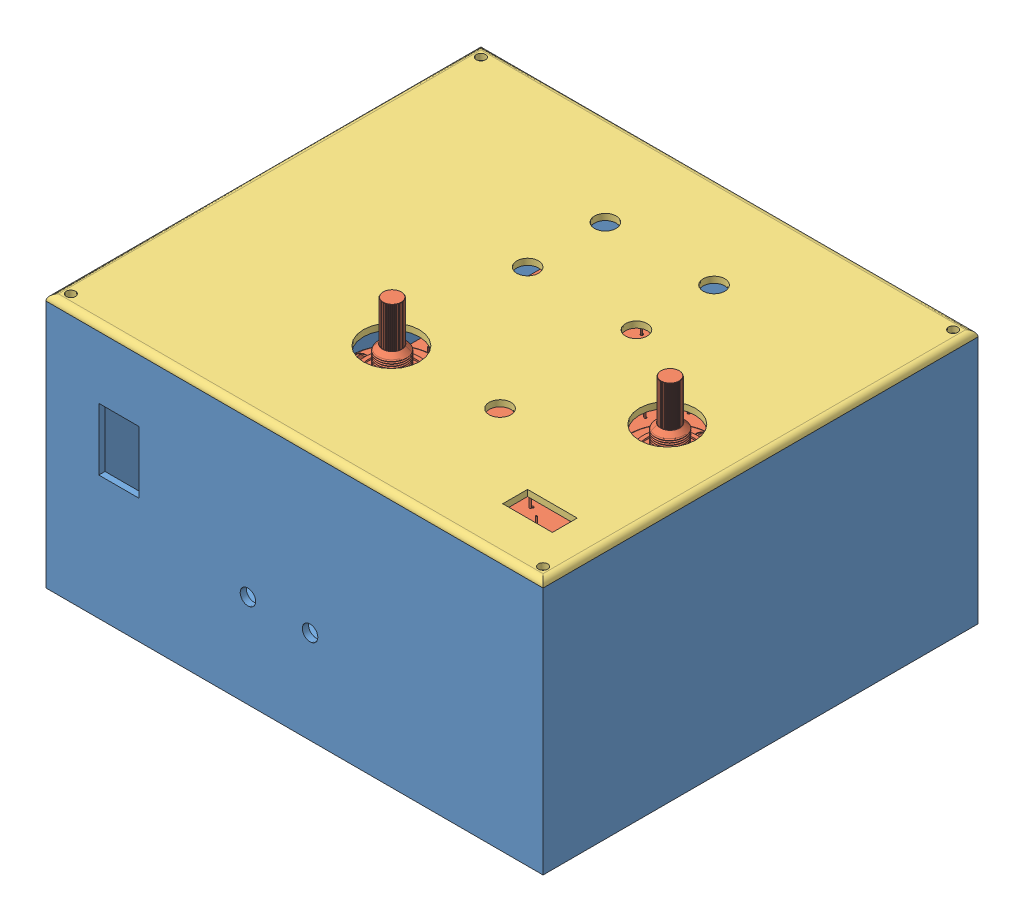
SolidWorks assembly Assembled, configuration Default. Lengths in mm.
Overall size (160 95.54 140).
4 component instances, 4 part files, 2 mates.
Components (placement in the parent):
- Part1-1: Part1 [Default] at (-22.4579 -40.3027 12.0564) size (160 80 140)
- pcb-1: pcb [Default] at (-49.4175 21.6973 -37.9881) x (1 0 -0.000604) z (0 -1 0) size (102.5 100 47.18)
- Part 2N-2: Part 2N [Default] at (-22.4579 39.6973 12.0564) size (160 2 140)
- power-2: power [Default] at (-29.2328 -27.8912 42.2061) x (0.999997 0 -0.002633) z (0 1 0) size (60 60 24.4)
Mates (geometry in assembly coordinates):
- Coincident3: coincident anti-aligned: circle of Part1-1; circle of pcb-1
- Coincident6: coincident aligned: circle of Part1-1; circle of power-2
